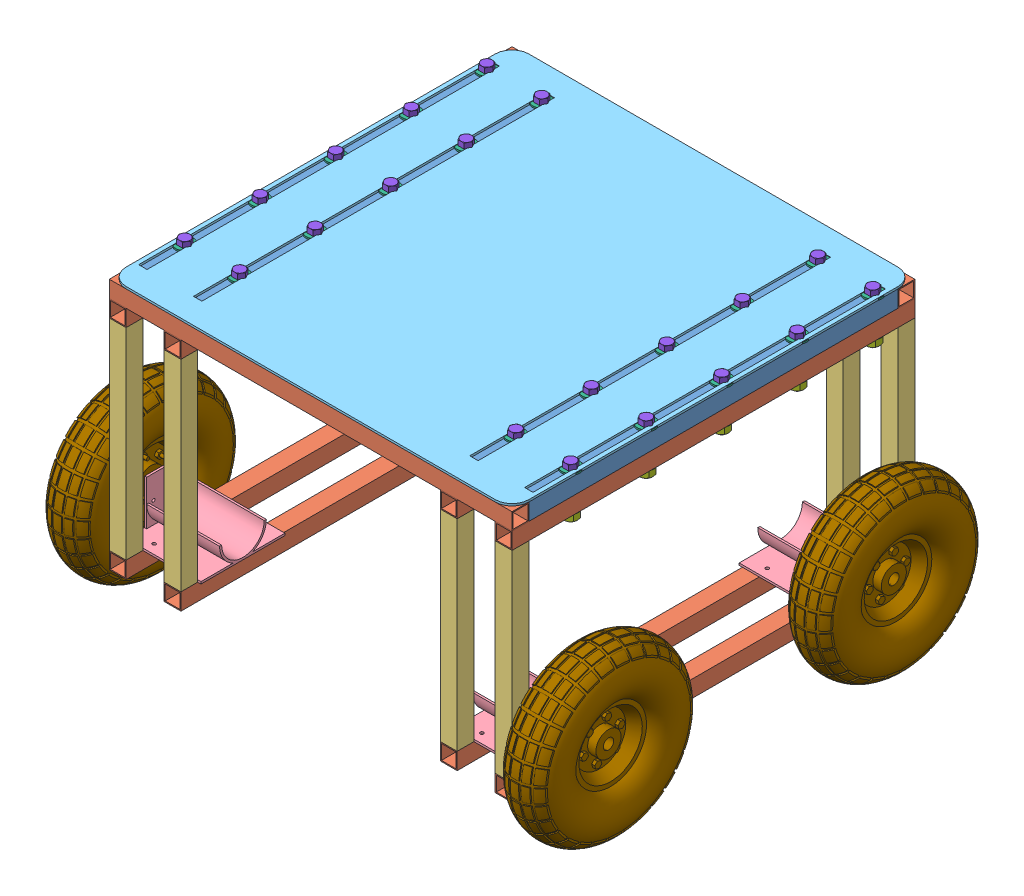
SolidWorks assembly framePlated, configuration Default. Lengths in mm.
Overall size (768.35 508.36 755.39).
117 component instances, 9 part files, 71 mates.
Components (placement in the parent):
- frame4shell-1: frame4shell [Default] at (-159.8395 504.2867 213.7177) size (609.6 381 609.6)
  - topPlate-1: topPlate [Default] at origin size (609.6 25.4 609.6)
    - 22_stube-1: 22_stube [Default] at (12.7 0 571.5) x (1 0 0) z (0 1 0) size (25.4 558.8 25.4)
    - 22_stube-2: 22_stube [Default] at (95.758 0 571.5) x (1 0 0) z (0 1 0) size (25.4 558.8 25.4)
    - 22_stube-3: 22_stube [Default] at (596.9 0 571.5) x (1 0 0) z (0 1 0) size (25.4 558.8 25.4)
    - 22_stube-4: 22_stube [Default] at (513.842 0 571.5) x (1 0 0) z (0 1 0) size (25.4 558.8 25.4)
    - 24_stube-1: 24_stube [Default] x (0 -1 0) z (0 0 1) size (25.4 609.6 25.4)
    - 24_stube-2: 24_stube [Default] at (609.6 0 584.2) x (0 1 0) z (0 0 1) size (25.4 609.6 25.4)
  - hangDownDrilled-1: hangDownDrilled [Default] at (12.7 -342.9 584.2) size (25.4 355.6 609.6)
    - 12_stube-1: 12_stube [Default] at origin size (25.4 304.8 25.4)
    - 24_stube-1: 24_stube [Default] at (0 -12.7 12.7) x (1 0 0) z (0 1 0) size (25.4 609.6 25.4)
    - 24_stube-2: 24_stube [Default] at (0 317.5 -596.9) x (0 -1 0) z (-1 0 0) size (25.4 609.6 25.4)
    - 12_stube-2: 12_stube [Default] at (0 304.8 -584.2) x (-1 0 0) z (0 0 1) size (25.4 304.8 25.4)
  - hangDownDrilled-2: hangDownDrilled [Default] at (95.758 -342.9 584.2) size (25.4 355.6 609.6)
    - 12_stube-1: 12_stube [Default] at origin size (25.4 304.8 25.4)
    - 24_stube-1: 24_stube [Default] at (0 -12.7 12.7) x (1 0 0) z (0 1 0) size (25.4 609.6 25.4)
    - 24_stube-2: 24_stube [Default] at (0 317.5 -596.9) x (0 -1 0) z (-1 0 0) size (25.4 609.6 25.4)
    - 12_stube-2: 12_stube [Default] at (0 304.8 -584.2) x (-1 0 0) z (0 0 1) size (25.4 304.8 25.4)
  - hangDownDrilled-3: hangDownDrilled [Default] at (513.842 -342.9 584.2) size (25.4 355.6 609.6)
    - 12_stube-1: 12_stube [Default] at origin size (25.4 304.8 25.4)
    - 24_stube-1: 24_stube [Default] at (0 -12.7 12.7) x (1 0 0) z (0 1 0) size (25.4 609.6 25.4)
    - 24_stube-2: 24_stube [Default] at (0 317.5 -596.9) x (0 -1 0) z (-1 0 0) size (25.4 609.6 25.4)
    - 12_stube-2: 12_stube [Default] at (0 304.8 -584.2) x (-1 0 0) z (0 0 1) size (25.4 304.8 25.4)
  - hangDownDrilled-4: hangDownDrilled [Default] at (596.9 -342.9 584.2) size (25.4 355.6 609.6)
    - 12_stube-1: 12_stube [Default] at origin size (25.4 304.8 25.4)
    - 24_stube-1: 24_stube [Default] at (0 -12.7 12.7) x (1 0 0) z (0 1 0) size (25.4 609.6 25.4)
    - 24_stube-2: 24_stube [Default] at (0 317.5 -596.9) x (0 -1 0) z (-1 0 0) size (25.4 609.6 25.4)
    - 12_stube-2: 12_stube [Default] at (0 304.8 -584.2) x (-1 0 0) z (0 0 1) size (25.4 304.8 25.4)
  - motor mount-1: motor mount [Default] at (496.189 -307.5178 508) x (0 0 -1) z (1 0 0) size (127 70.87 113.41)
  - motor mount-2: motor mount [Default] at (113.411 -307.5178 508) x (0 0 1) z (-1 0 0) size (127 70.87 113.41)
  - motor mount-3: motor mount [Default] at (496.189 -307.5178 76.2) x (0 0 -1) z (1 0 0) size (127 70.87 113.41)
  - motor mount-4: motor mount [Default] at (113.411 -307.5178 76.2) x (0 0 1) z (-1 0 0) size (127 70.87 113.41)
- plate_Sheet-1: plate_Sheet [Default] at (144.9605 516.9867 505.8177) size (609.6 3.17 609.6)
- flat washer type a narrow_ai-21: flat washer type a narrow_ai [Preferred Narrow FW 0.4375] at (437.0605 466.1867 251.8177) x (0 1 0) z (0 0 1) size (1.65 23.42 23.42)
- hex nut_ai-11: hex nut_ai [HNUT 0.5000-20-D-N] at (437.0605 453.1565 251.8177) x (1 0 0) z (0 -1 0) size (19.05 22 11.38)
- flat washer type a narrow_ai-22: flat washer type a narrow_ai [Preferred Narrow FW 0.4375] at (354.0025 466.1867 251.8177) x (0 1 0) z (0 0 1) size (1.65 23.42 23.42)
- hex nut_ai-12: hex nut_ai [HNUT 0.5000-20-D-N] at (354.0025 453.1565 251.8177) x (1 0 0) z (0 -1 0) size (19.05 22 11.38)
- flat washer type a narrow_ai-23: flat washer type a narrow_ai [Preferred Narrow FW 0.4375] at (354.0025 466.1867 366.1177) x (0 1 0) z (0 0 1) size (1.65 23.42 23.42)
- hex nut_ai-13: hex nut_ai [HNUT 0.5000-20-D-N] at (354.0025 453.1565 366.1177) x (1 0 0) z (0 -1 0) size (19.05 22 11.38)
- flat washer type a narrow_ai-24: flat washer type a narrow_ai [Preferred Narrow FW 0.4375] at (354.0025 466.1867 480.4177) x (0 1 0) z (0 0 1) size (1.65 23.42 23.42)
- hex nut_ai-14: hex nut_ai [HNUT 0.5000-20-D-N] at (354.0025 453.1565 480.4177) x (1 0 0) z (0 -1 0) size (19.05 22 11.38)
- flat washer type a narrow_ai-25: flat washer type a narrow_ai [Preferred Narrow FW 0.4375] at (354.0025 466.1867 594.7177) x (0 1 0) z (0 0 1) size (1.65 23.42 23.42)
- hex nut_ai-15: hex nut_ai [HNUT 0.5000-20-D-N] at (354.0025 453.1565 594.7177) x (1 0 0) z (0 -1 0) size (19.05 22 11.38)
- flat washer type a narrow_ai-26: flat washer type a narrow_ai [Preferred Narrow FW 0.4375] at (354.0025 466.1867 709.0177) x (0 1 0) z (0 0 1) size (1.65 23.42 23.42)
- hex nut_ai-16: hex nut_ai [HNUT 0.5000-20-D-N] at (354.0025 453.1565 709.0177) x (1 0 0) z (0 -1 0) size (19.05 22 11.38)
- flat washer type a narrow_ai-27: flat washer type a narrow_ai [Preferred Narrow FW 0.4375] at (437.0605 466.1867 366.1177) x (0 1 0) z (0 0 1) size (1.65 23.42 23.42)
- hex nut_ai-17: hex nut_ai [HNUT 0.5000-20-D-N] at (437.0605 453.1565 366.1177) x (1 0 0) z (0 -1 0) size (19.05 22 11.38)
- flat washer type a narrow_ai-28: flat washer type a narrow_ai [Preferred Narrow FW 0.4375] at (437.0605 466.1867 480.4177) x (0 1 0) z (0 0 1) size (1.65 23.42 23.42)
- hex nut_ai-18: hex nut_ai [HNUT 0.5000-20-D-N] at (437.0605 453.1565 480.4177) x (1 0 0) z (0 -1 0) size (19.05 22 11.38)
- flat washer type a narrow_ai-29: flat washer type a narrow_ai [Preferred Narrow FW 0.4375] at (437.0605 466.1867 594.7177) x (0 1 0) z (0 0 1) size (1.65 23.42 23.42)
- hex nut_ai-19: hex nut_ai [HNUT 0.5000-20-D-N] at (437.0605 453.1565 594.7177) x (1 0 0) z (0 -1 0) size (19.05 22 11.38)
- flat washer type a narrow_ai-30: flat washer type a narrow_ai [Preferred Narrow FW 0.4375] at (437.0605 466.1867 709.0177) x (0 1 0) z (0 0 1) size (1.65 23.42 23.42)
- hex nut_ai-20: hex nut_ai [HNUT 0.5000-20-D-N] at (437.0605 453.1565 709.0177) x (1 0 0) z (0 -1 0) size (19.05 22 11.38)
- hex bolt_ai-1: hex bolt_ai [HBOLT 0.4375-20x2.75x1.125-N] at (437.0605 527.4261 251.8177) x (0 -1 0) z (0 0 1) size (77.88 18.33 15.88)
- hex bolt_ai-2: hex bolt_ai [HBOLT 0.4375-20x2.75x1.125-N] at (354.0025 527.4261 251.8177) x (0 -1 0) z (0 0 1) size (77.88 18.33 15.88)
- hex bolt_ai-3: hex bolt_ai [HBOLT 0.4375-20x2.75x1.125-N] at (354.0025 527.4261 366.1177) x (0 -1 0) z (0 0 1) size (77.88 18.33 15.88)
- hex bolt_ai-4: hex bolt_ai [HBOLT 0.4375-20x2.75x1.125-N] at (354.0025 527.4261 480.4177) x (0 -1 0) z (0 0 1) size (77.88 18.33 15.88)
- hex bolt_ai-5: hex bolt_ai [HBOLT 0.4375-20x2.75x1.125-N] at (354.0025 527.4261 594.7177) x (0 -1 0) z (0 0 1) size (77.88 18.33 15.88)
- hex bolt_ai-6: hex bolt_ai [HBOLT 0.4375-20x2.75x1.125-N] at (354.0025 527.4261 709.0177) x (0 -1 0) z (0 0 1) size (77.88 18.33 15.88)
- hex bolt_ai-7: hex bolt_ai [HBOLT 0.4375-20x2.75x1.125-N] at (437.0605 527.4261 366.1177) x (0 -1 0) z (0 0 1) size (77.88 18.33 15.88)
- hex bolt_ai-8: hex bolt_ai [HBOLT 0.4375-20x2.75x1.125-N] at (437.0605 527.4261 480.4177) x (0 -1 0) z (0 0 1) size (77.88 18.33 15.88)
- hex bolt_ai-9: hex bolt_ai [HBOLT 0.4375-20x2.75x1.125-N] at (437.0605 527.4261 594.7177) x (0 -1 0) z (0 0 1) size (77.88 18.33 15.88)
- hex bolt_ai-10: hex bolt_ai [HBOLT 0.4375-20x2.75x1.125-N] at (437.0605 527.4261 709.0177) x (0 -1 0) z (0 0 1) size (77.88 18.33 15.88)
- flat washer type a narrow_ai-41: flat washer type a narrow_ai [Preferred Narrow FW 0.5] at (437.0605 516.9867 251.8177) x (0 -1 0) z (0 0 1) size (2.41 26.97 26.97)
- flat washer type a narrow_ai-42: flat washer type a narrow_ai [Preferred Narrow FW 0.5] at (354.0025 516.9867 251.8177) x (0 -1 0) z (0 0 1) size (2.41 26.97 26.97)
- flat washer type a narrow_ai-43: flat washer type a narrow_ai [Preferred Narrow FW 0.5] at (354.0025 516.9867 366.1177) x (0 -1 0) z (0 0 1) size (2.41 26.97 26.97)
- flat washer type a narrow_ai-44: flat washer type a narrow_ai [Preferred Narrow FW 0.5] at (354.0025 516.9867 480.4177) x (0 -1 0) z (0 0 1) size (2.41 26.97 26.97)
- flat washer type a narrow_ai-45: flat washer type a narrow_ai [Preferred Narrow FW 0.5] at (354.0025 516.9867 594.7177) x (0 -1 0) z (0 0 1) size (2.41 26.97 26.97)
- flat washer type a narrow_ai-46: flat washer type a narrow_ai [Preferred Narrow FW 0.5] at (354.0025 516.9867 709.0177) x (0 -1 0) z (0 0 1) size (2.41 26.97 26.97)
- flat washer type a narrow_ai-47: flat washer type a narrow_ai [Preferred Narrow FW 0.5] at (437.0605 516.9867 366.1177) x (0 -1 0) z (0 0 1) size (2.41 26.97 26.97)
- flat washer type a narrow_ai-48: flat washer type a narrow_ai [Preferred Narrow FW 0.5] at (437.0605 516.9867 480.4177) x (0 -1 0) z (0 0 1) size (2.41 26.97 26.97)
- flat washer type a narrow_ai-49: flat washer type a narrow_ai [Preferred Narrow FW 0.5] at (437.0605 516.9867 594.7177) x (0 -1 0) z (0 0 1) size (2.41 26.97 26.97)
- flat washer type a narrow_ai-50: flat washer type a narrow_ai [Preferred Narrow FW 0.5] at (437.0605 516.9867 709.0177) x (0 -1 0) z (0 0 1) size (2.41 26.97 26.97)
- hex bolt_ai-11: hex bolt_ai [HBOLT 0.4375-20x2.75x1.125-N] at (-147.1395 527.4261 251.8177) x (0 -1 0) z (0 0 -1) size (77.88 18.33 15.88)
- hex bolt_ai-12: hex bolt_ai [HBOLT 0.4375-20x2.75x1.125-N] at (-64.0815 527.4261 251.8177) x (0 -1 0) z (0 0 -1) size (77.88 18.33 15.88)
- hex bolt_ai-13: hex bolt_ai [HBOLT 0.4375-20x2.75x1.125-N] at (-64.0815 527.4261 366.1177) x (0 -1 0) z (0 0 -1) size (77.88 18.33 15.88)
- hex bolt_ai-14: hex bolt_ai [HBOLT 0.4375-20x2.75x1.125-N] at (-64.0815 527.4261 480.4177) x (0 -1 0) z (0 0 -1) size (77.88 18.33 15.88)
- hex bolt_ai-15: hex bolt_ai [HBOLT 0.4375-20x2.75x1.125-N] at (-64.0815 527.4261 594.7177) x (0 -1 0) z (0 0 -1) size (77.88 18.33 15.88)
- hex bolt_ai-16: hex bolt_ai [HBOLT 0.4375-20x2.75x1.125-N] at (-64.0815 527.4261 709.0177) x (0 -1 0) z (0 0 -1) size (77.88 18.33 15.88)
- hex bolt_ai-17: hex bolt_ai [HBOLT 0.4375-20x2.75x1.125-N] at (-147.1395 527.4261 366.1177) x (0 -1 0) z (0 0 -1) size (77.88 18.33 15.88)
- hex bolt_ai-18: hex bolt_ai [HBOLT 0.4375-20x2.75x1.125-N] at (-147.1395 527.4261 480.4177) x (0 -1 0) z (0 0 -1) size (77.88 18.33 15.88)
- hex bolt_ai-19: hex bolt_ai [HBOLT 0.4375-20x2.75x1.125-N] at (-147.1395 527.4261 594.7177) x (0 -1 0) z (0 0 -1) size (77.88 18.33 15.88)
- hex bolt_ai-20: hex bolt_ai [HBOLT 0.4375-20x2.75x1.125-N] at (-147.1395 527.4261 709.0177) x (0 -1 0) z (0 0 -1) size (77.88 18.33 15.88)
- flat washer type a narrow_ai-51: flat washer type a narrow_ai [Preferred Narrow FW 0.4375] at (-147.1395 466.1867 251.8177) x (0 1 0) z (0 0 -1) size (1.65 23.42 23.42)
- flat washer type a narrow_ai-52: flat washer type a narrow_ai [Preferred Narrow FW 0.4375] at (-64.0815 466.1867 251.8177) x (0 1 0) z (0 0 -1) size (1.65 23.42 23.42)
- flat washer type a narrow_ai-53: flat washer type a narrow_ai [Preferred Narrow FW 0.4375] at (-64.0815 466.1867 366.1177) x (0 1 0) z (0 0 -1) size (1.65 23.42 23.42)
- flat washer type a narrow_ai-54: flat washer type a narrow_ai [Preferred Narrow FW 0.4375] at (-64.0815 466.1867 594.7177) x (0 1 0) z (0 0 -1) size (1.65 23.42 23.42)
- flat washer type a narrow_ai-55: flat washer type a narrow_ai [Preferred Narrow FW 0.4375] at (-64.0815 466.1867 480.4177) x (0 1 0) z (0 0 -1) size (1.65 23.42 23.42)
- flat washer type a narrow_ai-56: flat washer type a narrow_ai [Preferred Narrow FW 0.4375] at (-64.0815 466.1867 709.0177) x (0 1 0) z (0 0 -1) size (1.65 23.42 23.42)
- flat washer type a narrow_ai-57: flat washer type a narrow_ai [Preferred Narrow FW 0.4375] at (-147.1395 466.1867 366.1177) x (0 1 0) z (0 0 -1) size (1.65 23.42 23.42)
- flat washer type a narrow_ai-58: flat washer type a narrow_ai [Preferred Narrow FW 0.4375] at (-147.1395 466.1867 480.4177) x (0 1 0) z (0 0 -1) size (1.65 23.42 23.42)
- flat washer type a narrow_ai-59: flat washer type a narrow_ai [Preferred Narrow FW 0.4375] at (-147.1395 466.1867 594.7177) x (0 1 0) z (0 0 -1) size (1.65 23.42 23.42)
- flat washer type a narrow_ai-60: flat washer type a narrow_ai [Preferred Narrow FW 0.4375] at (-147.1395 466.1867 709.0177) x (0 1 0) z (0 0 -1) size (1.65 23.42 23.42)
- hex nut_ai-21: hex nut_ai [HNUT 0.5000-20-D-N] at (-147.1395 464.5357 251.8177) x (-1 0 0) z (0 1 0) size (19.05 22 11.38)
- hex nut_ai-22: hex nut_ai [HNUT 0.5000-20-D-N] at (-64.0815 464.5357 251.8177) x (-1 0 0) z (0 1 0) size (19.05 22 11.38)
- hex nut_ai-23: hex nut_ai [HNUT 0.5000-20-D-N] at (-64.0815 464.5357 366.1177) x (-1 0 0) z (0 1 0) size (19.05 22 11.38)
- hex nut_ai-24: hex nut_ai [HNUT 0.5000-20-D-N] at (-64.0815 464.5357 594.7177) x (-1 0 0) z (0 1 0) size (19.05 22 11.38)
- hex nut_ai-25: hex nut_ai [HNUT 0.5000-20-D-N] at (-64.0815 464.5357 709.0177) x (-1 0 0) z (0 1 0) size (19.05 22 11.38)
- hex nut_ai-26: hex nut_ai [HNUT 0.5000-20-D-N] at (-64.0815 464.5357 480.4177) x (-1 0 0) z (0 1 0) size (19.05 22 11.38)
- hex nut_ai-27: hex nut_ai [HNUT 0.5000-20-D-N] at (-147.1395 464.5357 366.1177) x (-1 0 0) z (0 1 0) size (19.05 22 11.38)
- hex nut_ai-28: hex nut_ai [HNUT 0.5000-20-D-N] at (-147.1395 464.5357 480.4177) x (-1 0 0) z (0 1 0) size (19.05 22 11.38)
- hex nut_ai-29: hex nut_ai [HNUT 0.5000-20-D-N] at (-147.1395 464.5357 594.7177) x (-1 0 0) z (0 1 0) size (19.05 22 11.38)
- flat washer type a narrow_ai-61: flat washer type a narrow_ai [Preferred Narrow FW 0.5] at (-147.1395 516.9867 251.8177) x (0 -1 0) z (0 0 -1) size (2.41 26.97 26.97)
- hex nut_ai-30: hex nut_ai [HNUT 0.5000-20-D-N] at (-147.1395 464.5357 709.0177) x (-1 0 0) z (0 1 0) size (19.05 22 11.38)
- flat washer type a narrow_ai-62: flat washer type a narrow_ai [Preferred Narrow FW 0.5] at (-64.0815 516.9867 251.8177) x (0 -1 0) z (0 0 -1) size (2.41 26.97 26.97)
- flat washer type a narrow_ai-63: flat washer type a narrow_ai [Preferred Narrow FW 0.5] at (-64.0815 516.9867 366.1177) x (0 -1 0) z (0 0 -1) size (2.41 26.97 26.97)
- flat washer type a narrow_ai-64: flat washer type a narrow_ai [Preferred Narrow FW 0.5] at (-64.0815 516.9867 480.4177) x (0 -1 0) z (0 0 -1) size (2.41 26.97 26.97)
- flat washer type a narrow_ai-65: flat washer type a narrow_ai [Preferred Narrow FW 0.5] at (-64.0815 516.9867 594.7177) x (0 -1 0) z (0 0 -1) size (2.41 26.97 26.97)
- flat washer type a narrow_ai-66: flat washer type a narrow_ai [Preferred Narrow FW 0.5] at (-64.0815 516.9867 709.0177) x (0 -1 0) z (0 0 -1) size (2.41 26.97 26.97)
- flat washer type a narrow_ai-67: flat washer type a narrow_ai [Preferred Narrow FW 0.5] at (-147.1395 516.9867 480.4177) x (0 -1 0) z (0 0 -1) size (2.41 26.97 26.97)
- flat washer type a narrow_ai-68: flat washer type a narrow_ai [Preferred Narrow FW 0.5] at (-147.1395 516.9867 366.1177) x (0 -1 0) z (0 0 -1) size (2.41 26.97 26.97)
- flat washer type a narrow_ai-69: flat washer type a narrow_ai [Preferred Narrow FW 0.5] at (-147.1395 516.9867 594.7177) x (0 -1 0) z (0 0 -1) size (2.41 26.97 26.97)
- flat washer type a narrow_ai-70: flat washer type a narrow_ai [Preferred Narrow FW 0.5] at (-147.1395 516.9867 709.0177) x (0 -1 0) z (0 0 -1) size (2.41 26.97 26.97)
- Pneumatic Tire- 10in-1: Pneumatic Tire- 10in [Default] at (-201.1145 196.7689 721.7177) x (0 0.801885 0.597478) z (-1 0 0) size (253.96 254 76.2)
- Pneumatic Tire- 10in-2: Pneumatic Tire- 10in [Default] at (-201.1145 196.7689 289.9177) x (0 -0.159153 -0.987254) z (-1 0 0) size (253.96 254 76.2)
- Pneumatic Tire- 10in-3: Pneumatic Tire- 10in [Default] at (491.0355 196.7689 289.9177) x (0 -0.986808 -0.161892) z (1 0 0) size (253.96 254 76.2)
- Pneumatic Tire- 10in-4: Pneumatic Tire- 10in [Default] at (491.0355 196.7689 721.7177) x (0 -0.966926 -0.255058) z (1 0 0) size (253.96 254 76.2)
Mates (geometry in assembly coordinates):
- Coincident1: coincident anti-aligned: plane of frame4shell-1/topPlate-1/22_stube-2 through (-76.7815 516.9867 226.4177) normal (0 1 0); plane of plate_Sheet-1 through (144.9605 516.9867 505.8177) normal (0 -1 0)
- Coincident2: coincident aligned: plane of frame4shell-1/topPlate-1/22_stube-3 through (449.7605 516.9867 226.4177) normal (1 0 0); plane of plate_Sheet-1 through (449.7605 520.1617 810.6177) normal (1 0 0)
- Coincident3: coincident aligned: plane of frame4shell-1/topPlate-1/24_stube-2 through (-159.8395 491.5867 810.6177) normal (0 0 1); plane of plate_Sheet-1 through (-159.8395 520.1617 810.6177) normal (0 0 1)
- Coincident54: coincident anti-aligned: plane of frame4shell-1/hangDownDrilled-4/24_stube-2 through (424.3605 466.1867 810.6177) normal (0 -1 0); plane of flat washer type a narrow_ai-21 through (431.1042 466.1867 251.8177) normal (0 1 0)
- Coincident55: coincident anti-aligned: plane of flat washer type a narrow_ai-21 through (425.3511 464.5357 251.8177) normal (0 -1 0); plane of hex nut_ai-11 through (418.0105 464.5357 251.8177) normal (0 1 0)
- Coincident56: coincident anti-aligned: plane of frame4shell-1/hangDownDrilled-4/24_stube-2 through (424.3605 466.1867 810.6177) normal (0 -1 0); plane of flat washer type a narrow_ai-22 through (348.0462 466.1867 251.8177) normal (0 1 0)
- Coincident57: coincident anti-aligned: plane of flat washer type a narrow_ai-22 through (342.2931 464.5357 251.8177) normal (0 -1 0); plane of hex nut_ai-12 through (334.9525 464.5357 251.8177) normal (0 1 0)
- Coincident58: coincident anti-aligned: plane of frame4shell-1/hangDownDrilled-4/24_stube-2 through (424.3605 466.1867 810.6177) normal (0 -1 0); plane of flat washer type a narrow_ai-23 through (348.0462 466.1867 366.1177) normal (0 1 0)
- Coincident59: coincident anti-aligned: plane of flat washer type a narrow_ai-23 through (342.2931 464.5357 366.1177) normal (0 -1 0); plane of hex nut_ai-13 through (334.9525 464.5357 366.1177) normal (0 1 0)
- Coincident60: coincident anti-aligned: plane of frame4shell-1/hangDownDrilled-4/24_stube-2 through (424.3605 466.1867 810.6177) normal (0 -1 0); plane of flat washer type a narrow_ai-24 through (348.0462 466.1867 480.4177) normal (0 1 0)
- Coincident61: coincident anti-aligned: plane of flat washer type a narrow_ai-24 through (342.2931 464.5357 480.4177) normal (0 -1 0); plane of hex nut_ai-14 through (334.9525 464.5357 480.4177) normal (0 1 0)
- Coincident62: coincident anti-aligned: plane of frame4shell-1/hangDownDrilled-4/24_stube-2 through (424.3605 466.1867 810.6177) normal (0 -1 0); plane of flat washer type a narrow_ai-25 through (348.0462 466.1867 594.7177) normal (0 1 0)
- Coincident63: coincident anti-aligned: plane of flat washer type a narrow_ai-25 through (342.2931 464.5357 594.7177) normal (0 -1 0); plane of hex nut_ai-15 through (334.9525 464.5357 594.7177) normal (0 1 0)
- Coincident64: coincident anti-aligned: plane of frame4shell-1/hangDownDrilled-4/24_stube-2 through (424.3605 466.1867 810.6177) normal (0 -1 0); plane of flat washer type a narrow_ai-26 through (348.0462 466.1867 709.0177) normal (0 1 0)
- Coincident65: coincident anti-aligned: plane of flat washer type a narrow_ai-26 through (342.2931 464.5357 709.0177) normal (0 -1 0); plane of hex nut_ai-16 through (334.9525 464.5357 709.0177) normal (0 1 0)
- Coincident66: coincident anti-aligned: plane of frame4shell-1/hangDownDrilled-4/24_stube-2 through (424.3605 466.1867 810.6177) normal (0 -1 0); plane of flat washer type a narrow_ai-27 through (431.1042 466.1867 366.1177) normal (0 1 0)
- Coincident67: coincident anti-aligned: plane of flat washer type a narrow_ai-27 through (425.3511 464.5357 366.1177) normal (0 -1 0); plane of hex nut_ai-17 through (418.0105 464.5357 366.1177) normal (0 1 0)
- Coincident68: coincident anti-aligned: plane of frame4shell-1/hangDownDrilled-4/24_stube-2 through (424.3605 466.1867 810.6177) normal (0 -1 0); plane of flat washer type a narrow_ai-28 through (431.1042 466.1867 480.4177) normal (0 1 0)
- Coincident69: coincident anti-aligned: plane of flat washer type a narrow_ai-28 through (425.3511 464.5357 480.4177) normal (0 -1 0); plane of hex nut_ai-18 through (418.0105 464.5357 480.4177) normal (0 1 0)
- Coincident70: coincident anti-aligned: plane of frame4shell-1/hangDownDrilled-4/24_stube-2 through (424.3605 466.1867 810.6177) normal (0 -1 0); plane of flat washer type a narrow_ai-29 through (431.1042 466.1867 594.7177) normal (0 1 0)
- Coincident71: coincident anti-aligned: plane of flat washer type a narrow_ai-29 through (425.3511 464.5357 594.7177) normal (0 -1 0); plane of hex nut_ai-19 through (418.0105 464.5357 594.7177) normal (0 1 0)
- Coincident72: coincident anti-aligned: plane of frame4shell-1/hangDownDrilled-4/24_stube-2 through (424.3605 466.1867 810.6177) normal (0 -1 0); plane of flat washer type a narrow_ai-30 through (431.1042 466.1867 709.0177) normal (0 1 0)
- Coincident73: coincident anti-aligned: plane of flat washer type a narrow_ai-30 through (425.3511 464.5357 709.0177) normal (0 -1 0); plane of hex nut_ai-20 through (418.0105 464.5357 709.0177) normal (0 1 0)
- Concentric111: concentric aligned: cylinder of hex bolt_ai-1 through (437.0605 527.4261 251.8177) axis (0 1 0) radius 5.5563; cylinder of flat washer type a narrow_ai-41 through (437.0605 551.9117 251.8177) axis (0 1 0) radius 6.7437
- Coincident114: coincident anti-aligned: plane of frame4shell-1/topPlate-1/22_stube-3 through (424.3605 516.9867 226.4177) normal (0 1 0); plane of flat washer type a narrow_ai-41 through (443.8042 516.9867 251.8177) normal (0 -1 0)
- Concentric1121: concentric aligned: cylinder of frame4shell-1/topPlate-1/22_stube-3 through (437.0605 466.1867 251.8177) axis (0 1 0) radius 6.35; cylinder of hex bolt_ai-1 through (437.0605 527.4261 251.8177) axis (0 1 0) radius 5.5563
- Coincident1151: coincident anti-aligned: plane of hex bolt_ai-1 through (446.226 519.3997 251.8177) normal (0 -1 0); plane of flat washer type a narrow_ai-41 through (450.5479 519.3997 251.8177) normal (0 1 0)
- Concentric113: concentric aligned: cylinder of hex bolt_ai-2 through (354.0025 527.4261 251.8177) axis (0 1 0) radius 5.5563; cylinder of flat washer type a narrow_ai-42 through (354.0025 551.9117 251.8177) axis (0 1 0) radius 6.7437
- Coincident116: coincident anti-aligned: plane of frame4shell-1/topPlate-1/22_stube-3 through (424.3605 516.9867 226.4177) normal (0 1 0); plane of flat washer type a narrow_ai-42 through (360.7462 516.9867 251.8177) normal (0 -1 0)
- Concentric1141: concentric aligned: cylinder of frame4shell-1/topPlate-1/22_stube-4 through (354.0025 466.1867 251.8177) axis (0 1 0) radius 6.35; cylinder of hex bolt_ai-2 through (354.0025 527.4261 251.8177) axis (0 1 0) radius 5.5563
- Coincident1171: coincident anti-aligned: plane of hex bolt_ai-2 through (363.168 519.3997 251.8177) normal (0 -1 0); plane of flat washer type a narrow_ai-42 through (367.4899 519.3997 251.8177) normal (0 1 0)
- Concentric115: concentric aligned: cylinder of hex bolt_ai-3 through (354.0025 527.4261 366.1177) axis (0 1 0) radius 5.5563; cylinder of flat washer type a narrow_ai-43 through (354.0025 551.9117 366.1177) axis (0 1 0) radius 6.7437
- Coincident118: coincident anti-aligned: plane of frame4shell-1/topPlate-1/22_stube-3 through (424.3605 516.9867 226.4177) normal (0 1 0); plane of flat washer type a narrow_ai-43 through (360.7462 516.9867 366.1177) normal (0 -1 0)
- Concentric1161: concentric aligned: cylinder of frame4shell-1/topPlate-1/22_stube-4 through (354.0025 466.1867 366.1177) axis (0 1 0) radius 6.35; cylinder of hex bolt_ai-3 through (354.0025 527.4261 366.1177) axis (0 1 0) radius 5.5563
- Coincident1191: coincident anti-aligned: plane of hex bolt_ai-3 through (363.168 519.3997 366.1177) normal (0 -1 0); plane of flat washer type a narrow_ai-43 through (367.4899 519.3997 366.1177) normal (0 1 0)
- Concentric117: concentric aligned: cylinder of hex bolt_ai-4 through (354.0025 527.4261 480.4177) axis (0 1 0) radius 5.5563; cylinder of flat washer type a narrow_ai-44 through (354.0025 551.9117 480.4177) axis (0 1 0) radius 6.7437
- Coincident120: coincident anti-aligned: plane of frame4shell-1/topPlate-1/22_stube-3 through (424.3605 516.9867 226.4177) normal (0 1 0); plane of flat washer type a narrow_ai-44 through (360.7462 516.9867 480.4177) normal (0 -1 0)
- Concentric1181: concentric aligned: cylinder of frame4shell-1/topPlate-1/22_stube-4 through (354.0025 466.1867 480.4177) axis (0 1 0) radius 6.35; cylinder of hex bolt_ai-4 through (354.0025 527.4261 480.4177) axis (0 1 0) radius 5.5563
- Coincident1211: coincident anti-aligned: plane of hex bolt_ai-4 through (363.168 519.3997 480.4177) normal (0 -1 0); plane of flat washer type a narrow_ai-44 through (367.4899 519.3997 480.4177) normal (0 1 0)
- Concentric119: concentric aligned: cylinder of hex bolt_ai-5 through (354.0025 527.4261 594.7177) axis (0 1 0) radius 5.5563; cylinder of flat washer type a narrow_ai-45 through (354.0025 551.9117 594.7177) axis (0 1 0) radius 6.7437
- Coincident122: coincident anti-aligned: plane of frame4shell-1/topPlate-1/22_stube-3 through (424.3605 516.9867 226.4177) normal (0 1 0); plane of flat washer type a narrow_ai-45 through (360.7462 516.9867 594.7177) normal (0 -1 0)
- Concentric1201: concentric aligned: cylinder of frame4shell-1/topPlate-1/22_stube-4 through (354.0025 466.1867 594.7177) axis (0 1 0) radius 6.35; cylinder of hex bolt_ai-5 through (354.0025 527.4261 594.7177) axis (0 1 0) radius 5.5563
- Coincident1231: coincident anti-aligned: plane of hex bolt_ai-5 through (363.168 519.3997 594.7177) normal (0 -1 0); plane of flat washer type a narrow_ai-45 through (367.4899 519.3997 594.7177) normal (0 1 0)
- Concentric121: concentric aligned: cylinder of hex bolt_ai-6 through (354.0025 527.4261 709.0177) axis (0 1 0) radius 5.5563; cylinder of flat washer type a narrow_ai-46 through (354.0025 551.9117 709.0177) axis (0 1 0) radius 6.7437
- Coincident124: coincident anti-aligned: plane of frame4shell-1/topPlate-1/22_stube-3 through (424.3605 516.9867 226.4177) normal (0 1 0); plane of flat washer type a narrow_ai-46 through (360.7462 516.9867 709.0177) normal (0 -1 0)
- Concentric1221: concentric aligned: cylinder of frame4shell-1/topPlate-1/22_stube-4 through (354.0025 466.1867 709.0177) axis (0 1 0) radius 6.35; cylinder of hex bolt_ai-6 through (354.0025 527.4261 709.0177) axis (0 1 0) radius 5.5563
- Coincident1251: coincident anti-aligned: plane of hex bolt_ai-6 through (363.168 519.3997 709.0177) normal (0 -1 0); plane of flat washer type a narrow_ai-46 through (367.4899 519.3997 709.0177) normal (0 1 0)
- Concentric123: concentric aligned: cylinder of hex bolt_ai-7 through (437.0605 527.4261 366.1177) axis (0 1 0) radius 5.5563; cylinder of flat washer type a narrow_ai-47 through (437.0605 551.9117 366.1177) axis (0 1 0) radius 6.7437
- Coincident126: coincident anti-aligned: plane of frame4shell-1/topPlate-1/22_stube-3 through (424.3605 516.9867 226.4177) normal (0 1 0); plane of flat washer type a narrow_ai-47 through (443.8042 516.9867 366.1177) normal (0 -1 0)
- Concentric1241: concentric aligned: cylinder of frame4shell-1/topPlate-1/22_stube-3 through (437.0605 466.1867 366.1177) axis (0 1 0) radius 6.35; cylinder of hex bolt_ai-7 through (437.0605 527.4261 366.1177) axis (0 1 0) radius 5.5563
- Coincident1271: coincident anti-aligned: plane of hex bolt_ai-7 through (446.226 519.3997 366.1177) normal (0 -1 0); plane of flat washer type a narrow_ai-47 through (450.5479 519.3997 366.1177) normal (0 1 0)
- Concentric125: concentric aligned: cylinder of hex bolt_ai-8 through (437.0605 527.4261 480.4177) axis (0 1 0) radius 5.5563; cylinder of flat washer type a narrow_ai-48 through (437.0605 551.9117 480.4177) axis (0 1 0) radius 6.7437
- Coincident128: coincident anti-aligned: plane of frame4shell-1/topPlate-1/22_stube-3 through (424.3605 516.9867 226.4177) normal (0 1 0); plane of flat washer type a narrow_ai-48 through (443.8042 516.9867 480.4177) normal (0 -1 0)
- Concentric1261: concentric aligned: cylinder of frame4shell-1/topPlate-1/22_stube-3 through (437.0605 466.1867 480.4177) axis (0 1 0) radius 6.35; cylinder of hex bolt_ai-8 through (437.0605 527.4261 480.4177) axis (0 1 0) radius 5.5563
- Coincident1291: coincident anti-aligned: plane of hex bolt_ai-8 through (446.226 519.3997 480.4177) normal (0 -1 0); plane of flat washer type a narrow_ai-48 through (450.5479 519.3997 480.4177) normal (0 1 0)
- Concentric127: concentric aligned: cylinder of hex bolt_ai-9 through (437.0605 527.4261 594.7177) axis (0 1 0) radius 5.5563; cylinder of flat washer type a narrow_ai-49 through (437.0605 551.9117 594.7177) axis (0 1 0) radius 6.7437
- Coincident130: coincident anti-aligned: plane of frame4shell-1/topPlate-1/22_stube-3 through (424.3605 516.9867 226.4177) normal (0 1 0); plane of flat washer type a narrow_ai-49 through (443.8042 516.9867 594.7177) normal (0 -1 0)
- Concentric1281: concentric aligned: cylinder of frame4shell-1/topPlate-1/22_stube-3 through (437.0605 466.1867 594.7177) axis (0 1 0) radius 6.35; cylinder of hex bolt_ai-9 through (437.0605 527.4261 594.7177) axis (0 1 0) radius 5.5563
- Coincident1311: coincident anti-aligned: plane of hex bolt_ai-9 through (446.226 519.3997 594.7177) normal (0 -1 0); plane of flat washer type a narrow_ai-49 through (450.5479 519.3997 594.7177) normal (0 1 0)
- Concentric129: concentric aligned: cylinder of hex bolt_ai-10 through (437.0605 527.4261 709.0177) axis (0 1 0) radius 5.5563; cylinder of flat washer type a narrow_ai-50 through (437.0605 551.9117 709.0177) axis (0 1 0) radius 6.7437
- Coincident132: coincident anti-aligned: plane of frame4shell-1/topPlate-1/22_stube-3 through (424.3605 516.9867 226.4177) normal (0 1 0); plane of flat washer type a narrow_ai-50 through (443.8042 516.9867 709.0177) normal (0 -1 0)
- Concentric1301: concentric aligned: cylinder of frame4shell-1/topPlate-1/22_stube-3 through (437.0605 466.1867 709.0177) axis (0 1 0) radius 6.35; cylinder of hex bolt_ai-10 through (437.0605 527.4261 709.0177) axis (0 1 0) radius 5.5563
- Coincident1331: coincident anti-aligned: plane of hex bolt_ai-10 through (446.226 519.3997 709.0177) normal (0 -1 0); plane of flat washer type a narrow_ai-50 through (450.5479 519.3997 709.0177) normal (0 1 0)
- Concentric131: concentric aligned: circle of frame4shell-1/motor mount-4; circle of Pneumatic Tire- 10in-2
- Concentric132: concentric aligned: circle of frame4shell-1/motor mount-2; circle of Pneumatic Tire- 10in-1
- Concentric133: concentric aligned: circle of frame4shell-1/motor mount-1; circle of Pneumatic Tire- 10in-4
- Concentric134: concentric aligned: circle of frame4shell-1/motor mount-3; circle of Pneumatic Tire- 10in-3
- Distance1: distance = 25.4 mm anti-aligned: plane of Pneumatic Tire- 10in-2 through (-185.2395 196.7689 289.9177) normal (1 0 0); plane of frame4shell-1/motor mount-4 through (-159.8395 196.7689 289.9177) normal (-1 0 0)
- Distance2: distance = 25.4 mm anti-aligned: plane of Pneumatic Tire- 10in-1 through (-185.2395 196.7689 721.7177) normal (1 0 0); plane of frame4shell-1/motor mount-2 through (-159.8395 196.7689 721.7177) normal (-1 0 0)
- Distance3: distance = 25.4 mm anti-aligned: plane of Pneumatic Tire- 10in-3 through (475.1605 196.7689 289.9177) normal (-1 0 0); plane of frame4shell-1/motor mount-3 through (449.7605 196.7689 289.9177) normal (1 0 0)
- Distance4: distance = 25.4 mm anti-aligned: plane of Pneumatic Tire- 10in-4 through (475.1605 196.7689 721.7177) normal (-1 0 0); plane of frame4shell-1/motor mount-1 through (449.7605 196.7689 721.7177) normal (1 0 0)
